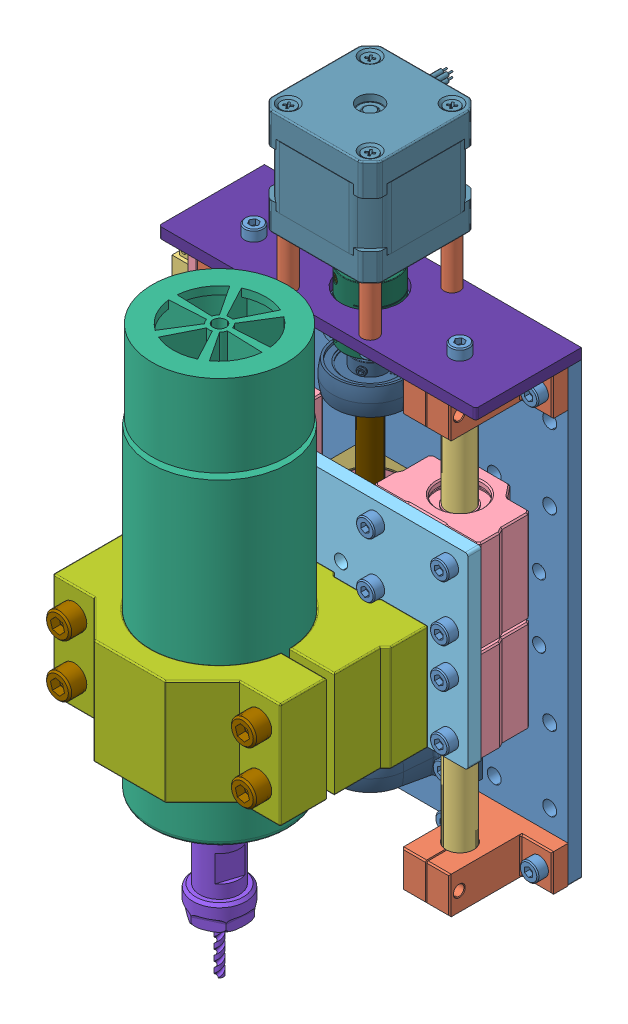
SolidWorks assembly eixoz_assembly, configuration Default. Lengths in mm.
Overall size (151.98 258.44 159.57).
72 component instances, 22 part files, 138 mates.
Components (placement in the parent):
- eixoz_backplate-1: eixoz_backplate [Default] at (6.0544 46.9928 189.1255) size (120 170 5)
- suporte_guia_sk10-1: suporte_guia_sk10 [Default] at (18.4754 216.9928 203.8715) x (1 0 0) z (0 -1 0) size (42 32.8 14)
- suporte_guia_sk10-2: suporte_guia_sk10 [Default] at (18.4754 60.9928 203.8715) x (1 0 0) z (0 -1 0) size (42 32.8 14)
- suporte_guia_sk10-3: suporte_guia_sk10 [Default] at (96.4754 216.9928 203.8715) x (1 0 0) z (0 -1 0) size (42 32.8 14)
- suporte_guia_sk10-4: suporte_guia_sk10 [Default] at (96.4754 60.9928 203.8715) x (1 0 0) z (0 -1 0) size (42 32.8 14)
- eixoz_eixo_linear-1: eixoz_eixo_linear [Default] at (27.0544 216.9928 214.1255) x (1 0 0) z (0 -1 0) size (10 10 170)
- eixoz_eixo_linear-2: eixoz_eixo_linear [Default] at (105.0544 216.9928 214.1255) x (1 0 0) z (0 -1 0) size (10 10 170)
- pillow_block_sc10uu-1: pillow_block_sc10uu [По умолчанию] at (27.0544 157.3616 214.1255) x (-1 0 0) z (0 -1 0) size (40 26 35)
- pillow_block_sc10uu-2: pillow_block_sc10uu [По умолчанию] at (105.0544 157.3616 214.1255) x (-1 0 0) z (0 -1 0) size (40 26 35)
- pillow_block_sc10uu-3: pillow_block_sc10uu [По умолчанию] at (27.0544 121.3616 214.1255) x (-1 0 0) z (0 -1 0) size (40 26 35)
- pillow_block_sc10uu-4: pillow_block_sc10uu [По умолчанию] at (105.0544 121.3616 214.1255) x (-1 0 0) z (0 -1 0) size (40 26 35)
- eixoz_frontplate-1: eixoz_frontplate [Default] at (6.0544 103.8616 227.1255) size (120 71 5)
- Assemb-1: Assemb [По умолчанию] at (16.0668 43.6518 129.8233) x (0.872476 0 0.488656) z (-0.488656 0 0.872476) size (112.81 214.81 109.59)
  - Spindle-1: Spindle [默认] at (110.2179 160.7098 94.4937) x (1 0 0) z (0 -1 0) size (52 52 178.5)
  - Spindle bracket-1: Spindle bracket [По умолчанию] at (132.865 60.2098 42.8399) x (0 1 0) z (0.872476 0 -0.488656) size (40 68 90)
  - ER11 Collet-1: ER11 Collet [默认] at (110.2179 10.2098 94.4937) x (-0.978997 0 0.203875) z (-0.203875 0 -0.978997) size (20.08 57.31 20.51)
  - socket head cap screw_ai-14: socket head cap screw_ai [HX-SHCS 0.25-28x2.5x2.5-N] at (92.5573 90.2098 134.5864) x (-0.488656 0 -0.872476) z (-0.838381 -0.276821 0.46956) size (69.85 9.53 9.53)
  - socket head cap screw_ai-16: socket head cap screw_ai [HX-SHCS 0.25-28x2.5x2.5-N] at (153.6306 90.2098 100.3804) x (-0.488656 0 -0.872476) z (-0.838381 -0.276821 0.46956) size (69.85 9.53 9.53)
  - socket head cap screw_ai-17: socket head cap screw_ai [HX-SHCS 0.25-28x2.5x2.5-N] at (92.5573 70.2098 134.5864) x (-0.488656 0 -0.872476) z (-0.838381 -0.276821 0.46956) size (69.85 9.53 9.53)
  - socket head cap screw_ai-18: socket head cap screw_ai [HX-SHCS 0.25-28x2.5x2.5-N] at (153.6306 70.2098 100.3804) x (-0.488656 0 -0.872476) z (-0.838381 -0.276821 0.46956) size (69.85 9.53 9.53)
- Pillow Block P08-1: Pillow Block P08 [Default] at (66.0544 69.4928 209.1255) x (1 0 0) z (0 -1 0) size (55 39.88 14.5)
- eixoz_espacador_castanha-1: eixoz_espacador_castanha [Default] at (48.5544 124.3616 223.1255) size (35 30 4)
- suporte_castanha_tr8-1: suporte_castanha_tr8 [Default] at (48.5544 124.3616 195.1255) size (35 30 28)
- castanha_tr8_2mm-1: castanha_tr8_2mm [Valor predeterminado] at (66.0544 150.3616 209.1255) size (22 13.71 22)
- Pillow Block P08-2: Pillow Block P08 [Default] at (66.0544 192.4928 209.1255) x (-1 0 0) z (0 1 0) size (55 39.88 14.5)
- motor_nema17_40mm-1: motor_nema17_40mm [По умолчанию] at (66.0544 280.9928 209.1255) x (1 0 0) z (0 0 -1) size (42.3 62 51.35)
- Acople Flexible-1: Acople Flexible [Predeterminado] at (67.4461 228.9928 208.2738) x (0.446669 0 -0.894699) z (0 -1 0) size (20.77 20.77 25)
  - Acople FlexibleSLDPRT-1: Acople FlexibleSLDPRT [Predeterminado] at (-1.3837 -0.8648 0) size (20.77 20.77 25)
  - socket set screw cone point_am-7: socket set screw cone point_am [B18.3.6M - M3 x 0.5 x 6 Hex Socket Cone Pt. SS --N] at (-11.2647 -0.8648 22) x (1 0 0) z (0 -0.164849 0.986319) size (6 3 3)
  - socket set screw cone point_am-8: socket set screw cone point_am [B18.3.6M - M3 x 0.5 x 6 Hex Socket Cone Pt. SS --N] at (-11.1909 -0.8648 3) x (1 0 0) z (0 0.00677 0.999977) size (6 3 3)
  - socket set screw cone point_am-9: socket set screw cone point_am [B18.3.6M - M3 x 0.5 x 6 Hex Socket Cone Pt. SS --N] at (-1.3837 -10.7654 3) x (0 1 0) z (-0.345086 0 0.938571) size (6 3 3)
  - socket set screw cone point_am-10: socket set screw cone point_am [B18.3.6M - M3 x 0.5 x 6 Hex Socket Cone Pt. SS --N] at (-1.3837 -10.5992 22) x (0 1 0) z (-0.865685 0 0.500588) size (6 3 3)
- eixoz_suporte_motor-1: eixoz_suporte_motor [Default] at (6.0544 220.9928 189.1255) x (1 0 0) z (0 -1 0) size (120 40 4)
- eixoz_fuso-1: eixoz_fuso [Default] at (66.0544 211.5428 209.1255) x (0.922618 0 0.385715) z (0 -1 0) size (8 8 150)
- socket head cap screw_am-1: socket head cap screw_am [B18.3.1M - 4 x 0.7 x 12 Hex SHCS -- 12NHX] at (11.0544 209.9928 206.1255) x (0 0 -1) z (1 0 0) size (16 7 7)
- socket head cap screw_am-2: socket head cap screw_am [B18.3.1M - 4 x 0.7 x 12 Hex SHCS -- 12NHX] at (43.0544 209.9928 204.1255) x (0 0 -1) z (1 0 0) size (16 7 7)
- socket head cap screw_am-3: socket head cap screw_am [B18.3.1M - 4 x 0.7 x 12 Hex SHCS -- 12NHX] at (89.0544 209.9928 204.1255) x (0 0 -1) z (1 0 0) size (16 7 7)
- socket head cap screw_am-4: socket head cap screw_am [B18.3.1M - 4 x 0.7 x 12 Hex SHCS -- 12NHX] at (121.0544 209.9928 204.1255) x (0 0 -1) z (1 0 0) size (16 7 7)
- socket head cap screw_am-5: socket head cap screw_am [B18.3.1M - 4 x 0.7 x 12 Hex SHCS -- 12NHX] at (121.0544 53.9928 204.1255) x (0 0 -1) z (1 0 0) size (16 7 7)
- socket head cap screw_am-6: socket head cap screw_am [B18.3.1M - 4 x 0.7 x 12 Hex SHCS -- 12NHX] at (89.0544 53.9928 204.1255) x (0 0 -1) z (1 0 0) size (16 7 7)
- socket head cap screw_am-7: socket head cap screw_am [B18.3.1M - 4 x 0.7 x 12 Hex SHCS -- 12NHX] at (11.0544 53.9928 206.1255) x (0 0 -1) z (1 0 0) size (16 7 7)
- socket head cap screw_am-8: socket head cap screw_am [B18.3.1M - 4 x 0.7 x 12 Hex SHCS -- 12NHX] at (43.0544 53.9928 204.1255) x (0 0 -1) z (1 0 0) size (16 7 7)
- socket head cap screw_am-9: socket head cap screw_am [B18.3.1M - 4 x 0.7 x 12 Hex SHCS -- 12NHX] at (45.0544 69.4928 203.1255) x (0 0 -1) z (1 0 0) size (16 7 7)
- socket head cap screw_am-10: socket head cap screw_am [B18.3.1M - 4 x 0.7 x 12 Hex SHCS -- 12NHX] at (87.0544 69.4928 203.1255) x (0 0 -1) z (1 0 0) size (16 7 7)
- socket head cap screw_am-11: socket head cap screw_am [B18.3.1M - 4 x 0.7 x 12 Hex SHCS -- 12NHX] at (13.0544 110.8616 236.1255) x (0 0 -1) z (1 0 0) size (16 7 7)
- socket head cap screw_am-12: socket head cap screw_am [B18.3.1M - 4 x 0.7 x 12 Hex SHCS -- 12NHX] at (13.0544 131.8616 236.1255) x (0 0 -1) z (1 0 0) size (16 7 7)
- socket head cap screw_am-13: socket head cap screw_am [B18.3.1M - 4 x 0.7 x 12 Hex SHCS -- 12NHX] at (13.0544 146.8616 236.1255) x (0 0 -1) z (1 0 0) size (16 7 7)
- socket head cap screw_am-14: socket head cap screw_am [B18.3.1M - 4 x 0.7 x 12 Hex SHCS -- 12NHX] at (13.0544 167.8616 236.1255) x (0 0 -1) z (1 0 0) size (16 7 7)
- socket head cap screw_am-15: socket head cap screw_am [B18.3.1M - 4 x 0.7 x 12 Hex SHCS -- 12NHX] at (41.0544 167.8616 236.1255) x (0 0 -1) z (0.99355 -0.113397 0) size (16 7 7)
- socket head cap screw_am-16: socket head cap screw_am [B18.3.1M - 4 x 0.7 x 12 Hex SHCS -- 12NHX] at (91.0544 167.8616 236.1255) x (0 0 -1) z (1 0 0) size (16 7 7)
- socket head cap screw_am-17: socket head cap screw_am [B18.3.1M - 4 x 0.7 x 12 Hex SHCS -- 12NHX] at (119.0544 167.8616 236.1255) x (0 0 -1) z (1 0 0) size (16 7 7)
- socket head cap screw_am-18: socket head cap screw_am [B18.3.1M - 4 x 0.7 x 12 Hex SHCS -- 12NHX] at (119.0544 146.8616 236.1255) x (0 0 -1) z (1 0 0) size (16 7 7)
- socket head cap screw_am-19: socket head cap screw_am [B18.3.1M - 4 x 0.7 x 12 Hex SHCS -- 12NHX] at (119.0544 131.8616 236.1255) x (0 0 -1) z (1 0 0) size (16 7 7)
- socket head cap screw_am-20: socket head cap screw_am [B18.3.1M - 4 x 0.7 x 12 Hex SHCS -- 12NHX] at (119.0544 110.8616 236.1255) x (0 0 -1) z (1 0 0) size (16 7 7)
- socket head cap screw_am-21: socket head cap screw_am [B18.3.1M - 4 x 0.7 x 12 Hex SHCS -- 12NHX] at (91.0544 146.8616 236.1255) x (0 0 -1) z (1 0 0) size (16 7 7)
- socket head cap screw_am-22: socket head cap screw_am [B18.3.1M - 4 x 0.7 x 12 Hex SHCS -- 12NHX] at (41.0544 146.8616 236.1255) x (0 0 -1) z (0.977293 -0.21189 0) size (16 7 7)
- socket head cap screw_am-23: socket head cap screw_am [B18.3.1M - 4 x 0.7 x 6 Hex SHCS -- 6NHX] at (87.0544 192.4928 203.1255) x (0 0 -1) z (1 0 0) size (10 7 7)
- socket head cap screw_am-24: socket head cap screw_am [B18.3.1M - 4 x 0.7 x 6 Hex SHCS -- 6NHX] at (45.0544 192.4928 203.1255) x (0 0 -1) z (1 0 0) size (10 7 7)
- eixoz_espacador_motor-1: eixoz_espacador_motor [Default] at (81.5544 240.9928 224.6255) x (1 0 0) z (0 -1 0) size (6 6 20)
- eixoz_espacador_motor-2: eixoz_espacador_motor [Default] at (50.5544 240.9928 224.6255) x (1 0 0) z (0 -1 0) size (6 6 20)
- eixoz_espacador_motor-3: eixoz_espacador_motor [Default] at (50.5544 240.9928 193.6255) x (1 0 0) z (0 -1 0) size (6 6 20)
- eixoz_espacador_motor-4: eixoz_espacador_motor [Default] at (81.5544 240.9928 193.6255) x (1 0 0) z (0 -1 0) size (6 6 20)
- socket head cap screw_am-25: socket head cap screw_am [B18.3.1M - 3 x 0.5 x 30 Hex SHCS -- 18NHX] at (81.5544 213.9928 224.6255) x (0 1 0) z (0 0 1) size (33 5.5 5.5)
- socket head cap screw_am-26: socket head cap screw_am [B18.3.1M - 3 x 0.5 x 30 Hex SHCS -- 18NHX] at (50.5544 213.9928 224.6255) x (0 1 0) z (0 0 1) size (33 5.5 5.5)
- socket head cap screw_am-29: socket head cap screw_am [B18.3.1M - 4 x 0.7 x 8 Hex SHCS -- 8NHX] at (105.0544 224.9928 214.1255) x (0 -1 0) z (0 0 1) size (12 7 7)
- socket head cap screw_am-30: socket head cap screw_am [B18.3.1M - 4 x 0.7 x 8 Hex SHCS -- 8NHX] at (27.0544 224.9928 214.1255) x (0 -1 0) z (0 0 1) size (12 7 7)
- socket head cap screw_am-31: socket head cap screw_am [B18.3.1M - 3 x 0.5 x 25 Hex SHCS -- 18NHX] at (50.5544 216.9928 193.6255) x (0 1 0) z (0 0 1) size (28 5.5 5.5)
- socket head cap screw_am-32: socket head cap screw_am [B18.3.1M - 3 x 0.5 x 25 Hex SHCS -- 18NHX] at (81.5544 216.9928 193.6255) x (0 1 0) z (0 0 1) size (28 5.5 5.5)
- switch_fim_de_curso_KW11-3Z-5-1: switch_fim_de_curso_KW11-3Z-5 [Default] at (14.8544 47.7567 226.9255) x (0 0 -1) z (0 1 0) size (25.09 6.4 19.9)
- switch_fim_de_curso_KW11-3Z-5-2: switch_fim_de_curso_KW11-3Z-5 [Default] at (8.8544 212.2407 226.9255) x (0 0 -1) z (0 -1 0) size (25.09 6.4 19.9)
- eixoz_suporte_switch_fim_curso-1: eixoz_suporte_switch_fim_curso [Default] at (18.0544 59.9928 200.1255) x (0 -1 0) z (-1 0 0) size (12 27 12)
- eixoz_suporte_switch_fim_curso-2: eixoz_suporte_switch_fim_curso [Default] at (18.0544 215.9928 200.1255) x (0 -1 0) z (-1 0 0) size (12 27 12)
Mates (geometry in assembly coordinates):
- Coincident1: coincident aligned: plane of suporte_guia_sk10-3 through (84.0544 202.9928 194.1255) normal (0 0 -1); plane of suporte_guia_sk10-4 through (84.0544 46.9928 194.1255) normal (0 0 -1)
- Coincident2: coincident aligned: plane of suporte_guia_sk10-1 through (6.0544 202.9928 194.1255) normal (0 0 -1); plane of suporte_guia_sk10-4 through (84.0544 46.9928 194.1255) normal (0 0 -1)
- Coincident3: coincident aligned: plane of suporte_guia_sk10-1 through (6.0544 202.9928 194.1255) normal (0 0 -1); plane of suporte_guia_sk10-2 through (6.0544 46.9928 194.1255) normal (0 0 -1)
- Coincident4: coincident aligned: plane of suporte_guia_sk10-1 through (6.0544 202.9928 200.1255) normal (-1 0 0); plane of suporte_guia_sk10-2 through (6.0544 46.9928 200.1255) normal (-1 0 0)
- Coincident5: coincident aligned: plane of suporte_guia_sk10-3 through (126.0544 202.9928 200.1255) normal (1 0 0); plane of suporte_guia_sk10-4 through (126.0544 46.9928 200.1255) normal (1 0 0)
- Coincident6: coincident anti-aligned: plane of eixoz_backplate-1 through (6.0544 46.9928 194.1255) normal (0 0 1); plane of suporte_guia_sk10-3 through (84.0544 202.9928 194.1255) normal (0 0 -1)
- Coincident7: coincident aligned: plane of eixoz_backplate-1 through (126.0544 46.9928 194.1255) normal (1 0 0); plane of suporte_guia_sk10-3 through (126.0544 202.9928 200.1255) normal (1 0 0)
- Parallel1: parallel aligned: plane of suporte_guia_sk10-1 through (6.0544 202.9928 200.1255) normal (-1 0 0); plane of eixoz_backplate-1 through (6.0544 46.9928 194.1255) normal (-1 0 0)
- Coincident9: coincident aligned: plane of eixoz_backplate-1 through (6.0544 46.9928 194.1255) normal (-1 0 0); plane of suporte_guia_sk10-1 through (6.0544 202.9928 200.1255) normal (-1 0 0)
- Coincident10: coincident aligned: plane of eixoz_backplate-1 through (6.0544 216.9928 194.1255) normal (0 1 0); plane of suporte_guia_sk10-1 through (18.4754 216.9928 203.8715) normal (0 1 0)
- Coincident11: coincident aligned: plane of eixoz_backplate-1 through (6.0544 216.9928 194.1255) normal (0 1 0); plane of suporte_guia_sk10-3 through (96.4754 216.9928 203.8715) normal (0 1 0)
- Coincident12: coincident aligned: plane of eixoz_backplate-1 through (6.0544 46.9928 194.1255) normal (0 -1 0); plane of suporte_guia_sk10-2 through (18.4754 46.9928 203.8715) normal (0 -1 0)
- Coincident13: coincident aligned: plane of eixoz_backplate-1 through (6.0544 46.9928 194.1255) normal (0 -1 0); plane of suporte_guia_sk10-4 through (96.4754 46.9928 203.8715) normal (0 -1 0)
- Coincident14: coincident aligned: plane of eixoz_eixo_linear-1 through (27.0544 216.9928 214.1255) normal (0 1 0); plane of eixoz_eixo_linear-2 through (105.0544 216.9928 214.1255) normal (0 1 0)
- Concentric1: concentric anti-aligned: cylinder of suporte_guia_sk10-1 through (27.0544 216.9928 214.1255) axis (0 -1 0) radius 5; cylinder of eixoz_eixo_linear-1 through (27.0544 46.9928 214.1255) axis (0 1 0) radius 5
- Concentric2: concentric anti-aligned: cylinder of suporte_guia_sk10-3 through (105.0544 216.9928 214.1255) axis (0 -1 0) radius 5; cylinder of eixoz_eixo_linear-2 through (105.0544 46.9928 214.1255) axis (0 1 0) radius 5
- Coincident15: coincident aligned: plane of suporte_guia_sk10-1 through (18.4754 216.9928 203.8715) normal (0 1 0); plane of eixoz_eixo_linear-1 through (27.0544 216.9928 214.1255) normal (0 1 0)
- Concentric3: concentric aligned: cylinder of eixoz_eixo_linear-2 through (105.0544 46.9928 214.1255) axis (0 1 0) radius 5; cylinder of pillow_block_sc10uu-2 through (105.0544 142.8616 214.1255) axis (0 1 0) radius 5
- Concentric4: concentric aligned: cylinder of eixoz_eixo_linear-2 through (105.0544 46.9928 214.1255) axis (0 1 0) radius 5; cylinder of pillow_block_sc10uu-4 through (105.0544 106.8616 214.1255) axis (0 1 0) radius 5
- Concentric5: concentric aligned: cylinder of eixoz_eixo_linear-1 through (27.0544 46.9928 214.1255) axis (0 1 0) radius 5; cylinder of pillow_block_sc10uu-1 through (27.0544 142.8616 214.1255) axis (0 1 0) radius 5
- Concentric6: concentric aligned: cylinder of eixoz_eixo_linear-1 through (27.0544 46.9928 214.1255) axis (0 1 0) radius 5; cylinder of pillow_block_sc10uu-3 through (27.0544 106.8616 214.1255) axis (0 1 0) radius 5
- Coincident16: coincident aligned: plane of pillow_block_sc10uu-1 through (27.0603 139.8616 226.6255) normal (0 0 1); plane of pillow_block_sc10uu-3 through (27.0603 103.8616 226.6255) normal (0 0 1)
- Coincident17: coincident aligned: plane of pillow_block_sc10uu-2 through (105.0603 139.8616 226.6255) normal (0 0 1); plane of pillow_block_sc10uu-4 through (105.0603 103.8616 226.6255) normal (0 0 1)
- Coincident18: coincident aligned: plane of pillow_block_sc10uu-1 through (27.0603 139.8616 226.6255) normal (0 0 1); plane of pillow_block_sc10uu-2 through (105.0603 139.8616 226.6255) normal (0 0 1)
- Distance1: distance = 71 mm anti-aligned: plane of pillow_block_sc10uu-3 through (27.0544 103.8616 214.1255) normal (0 -1 0); plane of pillow_block_sc10uu-1 through (27.0544 174.8616 214.1255) normal (0 1 0)
- Coincident20: coincident aligned: plane of pillow_block_sc10uu-1 through (27.0544 174.8616 214.1255) normal (0 1 0); plane of pillow_block_sc10uu-2 through (105.0544 174.8616 214.1255) normal (0 1 0)
- Coincident21: coincident aligned: plane of pillow_block_sc10uu-3 through (27.0544 103.8616 214.1255) normal (0 -1 0); plane of pillow_block_sc10uu-4 through (105.0544 103.8616 214.1255) normal (0 -1 0)
- Coincident22: coincident anti-aligned: plane of pillow_block_sc10uu-1 through (14.7427 139.8616 227.1255) normal (0 0 1); plane of eixoz_frontplate-1 through (6.0544 103.8616 227.1255) normal (0 0 -1)
- Coincident23: coincident aligned: plane of pillow_block_sc10uu-1 through (27.0544 174.8616 214.1255) normal (0 1 0); plane of eixoz_frontplate-1 through (6.0544 174.8616 232.1255) normal (0 1 0)
- Coincident24: coincident aligned: plane of eixoz_backplate-1 through (6.0544 46.9928 194.1255) normal (-1 0 0); plane of eixoz_frontplate-1 through (6.0544 103.8616 232.1255) normal (-1 0 0)
- Coincident25: coincident anti-aligned: plane of eixoz_frontplate-1 through (6.0544 103.8616 232.1255) normal (0 0 1); plane of Assemb-1/Spindle bracket-1 through (111.0544 143.8616 232.1255) normal (0 0 -1)
- Coincident28: coincident anti-aligned: plane of eixoz_backplate-1 through (6.0544 46.9928 194.1255) normal (0 0 1); plane of Pillow Block P08-1 through (66.0544 69.4928 194.1255) normal (0 0 -1)
- Distance4: distance = 16 mm aligned: plane of eixoz_backplate-1 through (6.0544 46.9928 194.1255) normal (0 -1 0); plane of Pillow Block P08-1 through (66.0544 62.9928 209.1255) normal (0 -1 0)
- Coincident32: coincident aligned: plane of eixoz_frontplate-1 through (6.0544 103.8616 232.1255) normal (0 -1 0); plane of Assemb-1/Spindle bracket-1 through (111.0544 103.8616 232.1255) normal (0 -1 0)
- Coincident34: coincident anti-aligned: plane of suporte_castanha_tr8-1 through (66.0544 150.3616 209.1255) normal (0 1 0); plane of castanha_tr8_2mm-1 through (66.0544 150.3616 209.1255) normal (0 -1 0)
- Concentric7: concentric aligned: circle of suporte_castanha_tr8-1; circle of castanha_tr8_2mm-1
- Coincident35: coincident anti-aligned: plane of eixoz_espacador_castanha-1 through (48.5544 124.3616 223.1255) normal (0 0 -1); plane of suporte_castanha_tr8-1 through (48.5544 124.3616 223.1255) normal (0 0 1)
- Coincident36: coincident aligned: plane of eixoz_espacador_castanha-1 through (83.5544 124.3616 227.1255) normal (1 0 0); plane of suporte_castanha_tr8-1 through (83.5544 124.3616 223.1255) normal (1 0 0)
- Coincident37: coincident aligned: plane of eixoz_espacador_castanha-1 through (48.5544 154.3616 227.1255) normal (0 1 0); plane of suporte_castanha_tr8-1 through (48.5544 154.3616 223.1255) normal (0 1 0)
- Coincident38: coincident anti-aligned: plane of eixoz_frontplate-1 through (6.0544 103.8616 227.1255) normal (0 0 -1); plane of eixoz_espacador_castanha-1 through (48.5544 124.3616 227.1255) normal (0 0 1)
- Coincident41: coincident anti-aligned: plane of eixoz_backplate-1 through (6.0544 46.9928 194.1255) normal (0 0 1); plane of Pillow Block P08-2 through (66.0544 192.4928 194.1255) normal (0 0 -1)
- Concentric8: concentric anti-aligned: cylinder of Pillow Block P08-1 through (66.0544 77.7301 209.1255) axis (0 1 0) radius 4; cylinder of Pillow Block P08-2 through (66.0544 184.2556 209.1255) axis (0 -1 0) radius 4
- Distance7: distance = 18 mm aligned: plane of Pillow Block P08-2 through (66.0544 198.9928 209.1255) normal (0 1 0); plane of eixoz_backplate-1 through (6.0544 216.9928 194.1255) normal (0 1 0)
- Concentric9: concentric anti-aligned: cylinder of Pillow Block P08-1 through (66.0544 77.7301 209.1255) axis (0 1 0) radius 4; cylinder of suporte_castanha_tr8-1 through (66.0544 132.3616 209.1255) axis (0 -1 0) radius 7
- Distance8: distance = 42.5 mm aligned: plane of suporte_castanha_tr8-1 through (83.5544 124.3616 223.1255) normal (1 0 0); plane of eixoz_backplate-1 through (126.0544 46.9928 194.1255) normal (1 0 0)
- Distance11: distance = 15 mm aligned: plane of Assemb-1/Spindle bracket-1 through (21.0544 143.8616 232.1255) normal (-1 0 0); plane of eixoz_frontplate-1 through (6.0544 103.8616 232.1255) normal (-1 0 0)
- Concentric10: concentric anti-aligned: cylinder of Pillow Block P08-2 through (66.0544 184.2556 209.1255) axis (0 -1 0) radius 4; cylinder of motor_nema17_40mm-1 through (66.0544 218.9928 209.1255) axis (0 1 0) radius 2.5
- Parallel4: parallel aligned: plane of eixoz_backplate-1 through (6.0544 46.9928 189.1255) normal (0 0 -1); plane of motor_nema17_40mm-1 through (66.0544 240.9928 188.1255) normal (0 0 -1)
- Concentric11: concentric aligned: cylinder of motor_nema17_40mm-1 through (66.0544 218.9928 209.1255) axis (0 1 0) radius 2.5; cylinder of Acople Flexible-1/Acople FlexibleSLDPRT-1 through (66.0544 203.9928 209.1255) axis (0 1 0) radius 2.5
- Distance12: distance = 10 mm anti-aligned: plane of Acople Flexible-1/Acople FlexibleSLDPRT-1 through (66.0544 228.9928 209.1255) normal (0 1 0); plane of motor_nema17_40mm-1 through (66.0544 238.9928 209.1255) normal (0 -1 0)
- Coincident49: coincident anti-aligned: plane of eixoz_backplate-1 through (6.0544 216.9928 194.1255) normal (0 1 0); plane of eixoz_suporte_motor-1 through (6.0544 216.9928 189.1255) normal (0 -1 0)
- Coincident50: coincident aligned: plane of eixoz_backplate-1 through (6.0544 46.9928 189.1255) normal (0 0 -1); plane of eixoz_suporte_motor-1 through (6.0544 216.9928 189.1255) normal (0 0 -1)
- Coincident51: coincident aligned: plane of eixoz_backplate-1 through (6.0544 46.9928 194.1255) normal (-1 0 0); plane of eixoz_suporte_motor-1 through (6.0544 216.9928 189.1255) normal (-1 0 0)
- Distance13: distance = 20 mm anti-aligned: plane of motor_nema17_40mm-1 through (66.0544 240.9928 209.1255) normal (0 -1 0); plane of eixoz_suporte_motor-1 through (6.0544 220.9928 189.1255) normal (0 1 0)
- Distance14: distance = 20.5 mm aligned: plane of suporte_castanha_tr8-1 through (48.5544 124.3616 223.1255) normal (0 -1 0); plane of eixoz_frontplate-1 through (6.0544 103.8616 232.1255) normal (0 -1 0)
- Concentric12: concentric aligned: cylinder of Pillow Block P08-1 through (66.0544 77.7301 209.1255) axis (0 1 0) radius 4; cylinder of eixoz_fuso-1 through (66.0544 61.5428 209.1255) axis (0 1 0) radius 4
- Coincident55: coincident aligned: plane of Pillow Block P08-1; plane of eixoz_fuso-1 through (66.0544 61.5428 209.1255) normal (0 -1 0)
- Concentric13: concentric anti-aligned: cone of suporte_guia_sk10-1 through (11.0544 209.9928 199.6255) axis (0 0 -1); cylinder of socket head cap screw_am-1 through (11.0544 209.9928 237.8755) axis (0 0 1) radius 3.5
- Coincident56: coincident anti-aligned: plane of eixoz_suporte_switch_fim_curso-2 through (6.0544 215.9928 202.1255) normal (0 0 1); plane of socket head cap screw_am-1 through (11.0544 213.4928 202.1255) normal (0 0 -1)
- Concentric14: concentric anti-aligned: cylinder of suporte_guia_sk10-1 through (43.0544 209.9928 199.6255) axis (0 0 -1) radius 785.3982; cylinder of socket head cap screw_am-2 through (43.0544 209.9928 235.8755) axis (0 0 1) radius 3.5
- Coincident57: coincident anti-aligned: plane of suporte_guia_sk10-1 through (36.0544 202.9928 200.1255) normal (0 0 1); plane of socket head cap screw_am-2 through (43.0544 213.4928 200.1255) normal (0 0 -1)
- Concentric15: concentric anti-aligned: cylinder of suporte_guia_sk10-3 through (89.0544 209.9928 199.6255) axis (0 0 -1) radius 785.3982; cylinder of socket head cap screw_am-3 through (89.0544 209.9928 235.8755) axis (0 0 1) radius 3.5
- Coincident58: coincident anti-aligned: plane of suporte_guia_sk10-3 through (84.0544 202.9928 200.1255) normal (0 0 1); plane of socket head cap screw_am-3 through (89.0544 213.4928 200.1255) normal (0 0 -1)
- Concentric16: concentric anti-aligned: cylinder of suporte_guia_sk10-3 through (121.0544 209.9928 199.6255) axis (0 0 -1) radius 785.3982; cylinder of socket head cap screw_am-4 through (121.0544 209.9928 235.8755) axis (0 0 1) radius 3.5
- Coincident59: coincident anti-aligned: plane of suporte_guia_sk10-3 through (114.0544 202.9928 200.1255) normal (0 0 1); plane of socket head cap screw_am-4 through (121.0544 213.4928 200.1255) normal (0 0 -1)
- Concentric17: concentric anti-aligned: cylinder of suporte_guia_sk10-4 through (121.0544 53.9928 199.6255) axis (0 0 -1) radius 785.3982; cylinder of socket head cap screw_am-5 through (121.0544 53.9928 235.8755) axis (0 0 1) radius 3.5
- Coincident60: coincident anti-aligned: plane of suporte_guia_sk10-4 through (114.0544 46.9928 200.1255) normal (0 0 1); plane of socket head cap screw_am-5 through (121.0544 57.4928 200.1255) normal (0 0 -1)
- Concentric18: concentric anti-aligned: cylinder of suporte_guia_sk10-4 through (89.0544 53.9928 199.6255) axis (0 0 -1) radius 785.3982; cylinder of socket head cap screw_am-6 through (89.0544 53.9928 235.8755) axis (0 0 1) radius 3.5
- Coincident61: coincident anti-aligned: plane of suporte_guia_sk10-4 through (84.0544 46.9928 200.1255) normal (0 0 1); plane of socket head cap screw_am-6 through (89.0544 57.4928 200.1255) normal (0 0 -1)
- Concentric19: concentric anti-aligned: cylinder of suporte_guia_sk10-2 through (11.0544 53.9928 199.6255) axis (0 0 -1) radius 785.3982; cylinder of socket head cap screw_am-7 through (11.0544 53.9928 237.8755) axis (0 0 1) radius 3.5
- Coincident62: coincident anti-aligned: plane of eixoz_suporte_switch_fim_curso-1 through (6.0544 59.9928 202.1255) normal (0 0 1); plane of socket head cap screw_am-7 through (11.0544 57.4928 202.1255) normal (0 0 -1)
- Concentric20: concentric anti-aligned: cylinder of suporte_guia_sk10-2 through (43.0544 53.9928 199.6255) axis (0 0 -1) radius 785.3982; cylinder of socket head cap screw_am-8 through (43.0544 53.9928 235.8755) axis (0 0 1) radius 3.5
- Coincident63: coincident anti-aligned: plane of suporte_guia_sk10-2 through (36.0544 46.9928 200.1255) normal (0 0 1); plane of socket head cap screw_am-8 through (43.0544 57.4928 200.1255) normal (0 0 -1)
- Concentric21: concentric aligned: cylinder of Pillow Block P08-1 through (45.0544 69.4928 193.1255) axis (0 0 1) radius 2.5; cylinder of socket head cap screw_am-9 through (45.0544 69.4928 234.8755) axis (0 0 1) radius 3.5
- Coincident64: coincident anti-aligned: plane of Pillow Block P08-1 through (66.0544 62.9928 199.1255) normal (0 0 1); plane of socket head cap screw_am-9 through (45.0544 72.9928 199.1255) normal (0 0 -1)
- Concentric22: concentric aligned: cylinder of Pillow Block P08-1 through (87.0544 69.4928 193.1255) axis (0 0 1) radius 2.5; cylinder of socket head cap screw_am-10 through (87.0544 69.4928 234.8755) axis (0 0 1) radius 3.5
- Coincident65: coincident anti-aligned: plane of Pillow Block P08-1 through (66.0544 62.9928 199.1255) normal (0 0 1); plane of socket head cap screw_am-10 through (87.0544 72.9928 199.1255) normal (0 0 -1)
- Concentric23: concentric anti-aligned: cylinder of eixoz_frontplate-1 through (13.0544 110.8616 273.1255) axis (0 0 -1) radius 2.65; cylinder of socket head cap screw_am-11 through (13.0544 110.8616 267.8755) axis (0 0 1) radius 3.5
- Coincident66: coincident anti-aligned: plane of eixoz_frontplate-1 through (6.0544 103.8616 232.1255) normal (0 0 1); plane of socket head cap screw_am-11 through (13.0544 114.3616 232.1255) normal (0 0 -1)
- Concentric24: concentric anti-aligned: cylinder of eixoz_frontplate-1 through (13.0544 131.8616 273.1255) axis (0 0 -1) radius 2.65; cylinder of socket head cap screw_am-12 through (13.0544 131.8616 267.8755) axis (0 0 1) radius 3.5
- Coincident67: coincident anti-aligned: plane of eixoz_frontplate-1 through (6.0544 103.8616 232.1255) normal (0 0 1); plane of socket head cap screw_am-12 through (13.0544 135.3616 232.1255) normal (0 0 -1)
- Concentric25: concentric anti-aligned: cylinder of eixoz_frontplate-1 through (13.0544 146.8616 273.1255) axis (0 0 -1) radius 2.65; cylinder of socket head cap screw_am-13 through (13.0544 146.8616 267.8755) axis (0 0 1) radius 3.5
- Coincident68: coincident anti-aligned: plane of eixoz_frontplate-1 through (6.0544 103.8616 232.1255) normal (0 0 1); plane of socket head cap screw_am-13 through (13.0544 150.3616 232.1255) normal (0 0 -1)
- Concentric26: concentric anti-aligned: cylinder of eixoz_frontplate-1 through (13.0544 167.8616 273.1255) axis (0 0 -1) radius 2.65; cylinder of socket head cap screw_am-14 through (13.0544 167.8616 267.8755) axis (0 0 1) radius 3.5
- Coincident69: coincident anti-aligned: plane of eixoz_frontplate-1 through (6.0544 103.8616 232.1255) normal (0 0 1); plane of socket head cap screw_am-14 through (13.0544 171.3616 232.1255) normal (0 0 -1)
- Concentric27: concentric anti-aligned: cylinder of eixoz_frontplate-1 through (41.0544 167.8616 273.1255) axis (0 0 -1) radius 2.65; cylinder of socket head cap screw_am-15 through (41.0544 167.8616 267.8755) axis (0 0 1) radius 3.5
- Coincident70: coincident anti-aligned: plane of eixoz_frontplate-1 through (6.0544 103.8616 232.1255) normal (0 0 1); plane of socket head cap screw_am-15 through (41.4512 171.339 232.1255) normal (0 0 -1)
- Concentric28: concentric anti-aligned: cylinder of eixoz_frontplate-1 through (91.0544 167.8616 273.1255) axis (0 0 -1) radius 2.65; cylinder of socket head cap screw_am-16 through (91.0544 167.8616 267.8755) axis (0 0 1) radius 3.5
- Coincident71: coincident anti-aligned: plane of eixoz_frontplate-1 through (6.0544 103.8616 232.1255) normal (0 0 1); plane of socket head cap screw_am-16 through (91.0544 171.3616 232.1255) normal (0 0 -1)
- Concentric29: concentric anti-aligned: cylinder of eixoz_frontplate-1 through (119.0544 167.8616 273.1255) axis (0 0 -1) radius 2.65; cylinder of socket head cap screw_am-17 through (119.0544 167.8616 267.8755) axis (0 0 1) radius 3.5
- Coincident72: coincident anti-aligned: plane of eixoz_frontplate-1 through (6.0544 103.8616 232.1255) normal (0 0 1); plane of socket head cap screw_am-17 through (119.0544 171.3616 232.1255) normal (0 0 -1)
- Concentric30: concentric anti-aligned: cylinder of eixoz_frontplate-1 through (119.0544 146.8616 273.1255) axis (0 0 -1) radius 2.65; cylinder of socket head cap screw_am-18 through (119.0544 146.8616 267.8755) axis (0 0 1) radius 3.5
- Coincident73: coincident anti-aligned: plane of eixoz_frontplate-1 through (6.0544 103.8616 232.1255) normal (0 0 1); plane of socket head cap screw_am-18 through (119.0544 150.3616 232.1255) normal (0 0 -1)
- Concentric31: concentric anti-aligned: cylinder of eixoz_frontplate-1 through (119.0544 131.8616 273.1255) axis (0 0 -1) radius 2.65; cylinder of socket head cap screw_am-19 through (119.0544 131.8616 267.8755) axis (0 0 1) radius 3.5
- Coincident74: coincident anti-aligned: plane of eixoz_frontplate-1 through (6.0544 103.8616 232.1255) normal (0 0 1); plane of socket head cap screw_am-19 through (119.0544 135.3616 232.1255) normal (0 0 -1)
- Concentric32: concentric anti-aligned: cylinder of eixoz_frontplate-1 through (119.0544 110.8616 273.1255) axis (0 0 -1) radius 2.65; cylinder of socket head cap screw_am-20 through (119.0544 110.8616 267.8755) axis (0 0 1) radius 3.5
- Coincident75: coincident anti-aligned: plane of eixoz_frontplate-1 through (6.0544 103.8616 232.1255) normal (0 0 1); plane of socket head cap screw_am-20 through (119.0544 114.3616 232.1255) normal (0 0 -1)
- Concentric331: concentric anti-aligned: cylinder of eixoz_frontplate-1 through (91.0544 146.8616 273.1255) axis (0 0 -1) radius 2.65; cylinder of socket head cap screw_am-21 through (91.0544 146.8616 267.8755) axis (0 0 1) radius 3.5
- Coincident761: coincident anti-aligned: plane of eixoz_frontplate-1 through (6.0544 103.8616 232.1255) normal (0 0 1); plane of socket head cap screw_am-21 through (91.0544 150.3616 232.1255) normal (0 0 -1)
- Concentric34: concentric anti-aligned: cylinder of eixoz_frontplate-1 through (41.0544 146.8616 273.1255) axis (0 0 -1) radius 2.65; cylinder of socket head cap screw_am-22 through (41.0544 146.8616 267.8755) axis (0 0 1) radius 3.5
- Coincident77: coincident anti-aligned: plane of eixoz_frontplate-1 through (6.0544 103.8616 232.1255) normal (0 0 1); plane of socket head cap screw_am-22 through (41.796 150.2821 232.1255) normal (0 0 -1)
- Concentric35: concentric aligned: cylinder of Pillow Block P08-2 through (87.0544 192.4928 193.1255) axis (0 0 1) radius 2.5; cylinder of socket head cap screw_am-23 through (87.0544 192.4928 234.8755) axis (0 0 1) radius 3.5
- Coincident78: coincident anti-aligned: plane of Pillow Block P08-2 through (66.0544 198.9928 199.1255) normal (0 0 1); plane of socket head cap screw_am-23 through (87.0544 195.9928 199.1255) normal (0 0 -1)
- Concentric36: concentric aligned: cylinder of Pillow Block P08-2 through (45.0544 192.4928 193.1255) axis (0 0 1) radius 2.5; cylinder of socket head cap screw_am-24 through (45.0544 192.4928 234.8755) axis (0 0 1) radius 3.5
- Coincident79: coincident anti-aligned: plane of Pillow Block P08-2 through (66.0544 198.9928 199.1255) normal (0 0 1); plane of socket head cap screw_am-24 through (45.0544 195.9928 199.1255) normal (0 0 -1)
- Coincident80: coincident aligned: plane of eixoz_espacador_motor-1 through (81.5544 240.9928 224.6255) normal (0 1 0); plane of eixoz_espacador_motor-2 through (50.5544 240.9928 224.6255) normal (0 1 0)
- Coincident81: coincident aligned: plane of eixoz_espacador_motor-1 through (81.5544 240.9928 224.6255) normal (0 1 0); plane of eixoz_espacador_motor-3 through (50.5544 240.9928 193.6255) normal (0 1 0)
- Coincident83: coincident aligned: plane of eixoz_espacador_motor-3 through (50.5544 240.9928 193.6255) normal (0 1 0); plane of eixoz_espacador_motor-4 through (81.5544 240.9928 193.6255) normal (0 1 0)
- Coincident84: coincident anti-aligned: plane of motor_nema17_40mm-1 through (66.0544 240.9928 209.1255) normal (0 -1 0); plane of eixoz_espacador_motor-3 through (50.5544 240.9928 193.6255) normal (0 1 0)
- Concentric37: concentric aligned: cylinder of eixoz_suporte_motor-1 through (50.5544 216.9928 193.6255) axis (0 1 0) radius 2; cylinder of eixoz_espacador_motor-3 through (50.5544 220.9928 193.6255) axis (0 1 0) radius 2
- Concentric38: concentric aligned: cylinder of eixoz_suporte_motor-1 through (50.5544 216.9928 224.6255) axis (0 1 0) radius 2; cylinder of eixoz_espacador_motor-2 through (50.5544 220.9928 224.6255) axis (0 1 0) radius 2
- Concentric39: concentric aligned: cylinder of eixoz_suporte_motor-1 through (81.5544 216.9928 224.6255) axis (0 1 0) radius 2; cylinder of eixoz_espacador_motor-1 through (81.5544 220.9928 224.6255) axis (0 1 0) radius 2
- Coincident85: coincident anti-aligned: cylinder of eixoz_suporte_motor-1; cylinder of eixoz_espacador_motor-4 through (81.5544 220.9928 193.6255) axis (0 1 0) radius 2
- Concentric40: concentric anti-aligned: cylinder of eixoz_suporte_motor-1 through (81.5544 216.9928 224.6255) axis (0 1 0) radius 2; cylinder of socket head cap screw_am-25 through (81.5544 182.2428 224.6255) axis (0 -1 0) radius 2.75
- Coincident86: coincident anti-aligned: plane of eixoz_suporte_motor-1 through (6.0544 216.9928 189.1255) normal (0 -1 0); plane of socket head cap screw_am-25 through (78.8044 216.9928 224.6255) normal (0 1 0)
- Concentric41: concentric anti-aligned: cylinder of eixoz_suporte_motor-1 through (50.5544 216.9928 224.6255) axis (0 1 0) radius 2; cylinder of socket head cap screw_am-26 through (50.5544 182.2428 224.6255) axis (0 -1 0) radius 2.75
- Coincident87: coincident anti-aligned: plane of eixoz_suporte_motor-1 through (6.0544 216.9928 189.1255) normal (0 -1 0); plane of socket head cap screw_am-26 through (47.8044 216.9928 224.6255) normal (0 1 0)
- Concentric44: concentric aligned: cylinder of eixoz_suporte_motor-1 through (105.0544 216.9928 214.1255) axis (0 1 0) radius 2.5; cylinder of socket head cap screw_am-29 through (105.0544 256.7428 214.1255) axis (0 1 0) radius 3.5
- Coincident90: coincident anti-aligned: plane of eixoz_suporte_motor-1 through (6.0544 220.9928 189.1255) normal (0 1 0); plane of socket head cap screw_am-29 through (108.5544 220.9928 214.1255) normal (0 -1 0)
- Concentric45: concentric aligned: cylinder of eixoz_suporte_motor-1 through (27.0544 216.9928 214.1255) axis (0 1 0) radius 2.5; cylinder of socket head cap screw_am-30 through (27.0544 256.7428 214.1255) axis (0 1 0) radius 3.5
- Coincident91: coincident anti-aligned: plane of eixoz_suporte_motor-1 through (6.0544 220.9928 189.1255) normal (0 1 0); plane of socket head cap screw_am-30 through (30.5544 220.9928 214.1255) normal (0 -1 0)
- Concentric46: concentric anti-aligned: cylinder of eixoz_suporte_motor-1 through (50.5544 216.9928 193.6255) axis (0 1 0) radius 2; cylinder of socket head cap screw_am-31 through (50.5544 185.2428 193.6255) axis (0 -1 0) radius 2.75
- Coincident92: coincident anti-aligned: plane of eixoz_suporte_motor-1 through (50.5544 219.9928 193.6255) normal (0 -1 0); plane of socket head cap screw_am-31 through (47.8044 219.9928 193.6255) normal (0 1 0)
- Concentric47: concentric anti-aligned: cylinder of eixoz_suporte_motor-1 through (81.5544 216.9928 193.6255) axis (0 1 0) radius 2; cylinder of socket head cap screw_am-32 through (81.5544 185.2428 193.6255) axis (0 -1 0) radius 2.75
- Coincident93: coincident anti-aligned: plane of eixoz_suporte_motor-1 through (81.5544 219.9928 193.6255) normal (0 -1 0); plane of socket head cap screw_am-32 through (78.8044 219.9928 193.6255) normal (0 1 0)
- LimitDistance1: limit distance = 28.1313 mm anti-aligned: plane of pillow_block_sc10uu-1 through (27.0544 174.8616 214.1255) normal (0 1 0); plane of suporte_guia_sk10-1 through (18.4754 202.9928 203.8715) normal (0 -1 0)
- Coincident765: coincident aligned: plane of switch_fim_de_curso_KW11-3Z-5-1 through (8.6544 47.7567 226.9255) normal (-1 0 0); plane of switch_fim_de_curso_KW11-3Z-5-2 through (8.6544 212.2407 226.9255) normal (-1 0 0)
- Coincident766: coincident aligned: plane of switch_fim_de_curso_KW11-3Z-5-1 through (14.8544 48.3567 226.9255) normal (0 0 1); plane of switch_fim_de_curso_KW11-3Z-5-2 through (8.8544 211.6407 226.9255) normal (0 0 1)
- Coincident767: coincident aligned: plane of suporte_guia_sk10-2 through (18.0544 46.9928 226.9255) normal (0 0 1); plane of switch_fim_de_curso_KW11-3Z-5-1 through (14.8544 48.3567 226.9255) normal (0 0 1)
- Coincident768: coincident anti-aligned: plane of suporte_guia_sk10-2 through (6.0544 46.9928 200.1255) normal (0 0 1); plane of eixoz_suporte_switch_fim_curso-1 through (15.0544 59.9928 200.1255) normal (0 0 -1)
- Coincident769: coincident anti-aligned: plane of suporte_guia_sk10-2 through (18.0544 46.9928 200.1255) normal (-1 0 0); plane of eixoz_suporte_switch_fim_curso-1 through (18.0544 59.9928 200.1255) normal (1 0 0)
- Distance15: distance = 1 mm aligned: plane of eixoz_suporte_switch_fim_curso-1 through (15.0544 47.9928 200.1255) normal (0 -1 0); plane of suporte_guia_sk10-2 through (18.4754 46.9928 203.8715) normal (0 -1 0)
- Coincident771: coincident anti-aligned: plane of switch_fim_de_curso_KW11-3Z-5-1 through (15.0544 47.7567 226.9255) normal (1 0 0); plane of eixoz_suporte_switch_fim_curso-1 through (15.0544 59.9928 200.1255) normal (-1 0 0)
- Concentric332: concentric aligned: cylinder of switch_fim_de_curso_KW11-3Z-5-1 through (14.8544 50.7567 221.9255) axis (-1 0 0) radius 1.2; cylinder of eixoz_suporte_switch_fim_curso-1 through (25.0544 50.7567 221.9255) axis (-1 0 0) radius 1.2
- Coincident772: coincident anti-aligned: plane of suporte_guia_sk10-1 through (6.0544 202.9928 200.1255) normal (0 0 1); plane of eixoz_suporte_switch_fim_curso-2 through (15.0544 215.9928 200.1255) normal (0 0 -1)
- Coincident773: coincident anti-aligned: plane of suporte_guia_sk10-1 through (18.0544 202.9928 200.1255) normal (-1 0 0); plane of eixoz_suporte_switch_fim_curso-2 through (18.0544 215.9928 200.1255) normal (1 0 0)
- Distance16: distance = 1 mm aligned: plane of eixoz_suporte_switch_fim_curso-2 through (15.0544 203.9928 200.1255) normal (0 -1 0); plane of suporte_guia_sk10-1 through (18.4754 202.9928 203.8715) normal (0 -1 0)
- Concentric333: concentric anti-aligned: cylinder of switch_fim_de_curso_KW11-3Z-5-2 through (8.8544 209.2407 221.9255) axis (1 0 0) radius 1.2; cylinder of eixoz_suporte_switch_fim_curso-2 through (25.0544 209.2407 221.9255) axis (-1 0 0) radius 1.2
